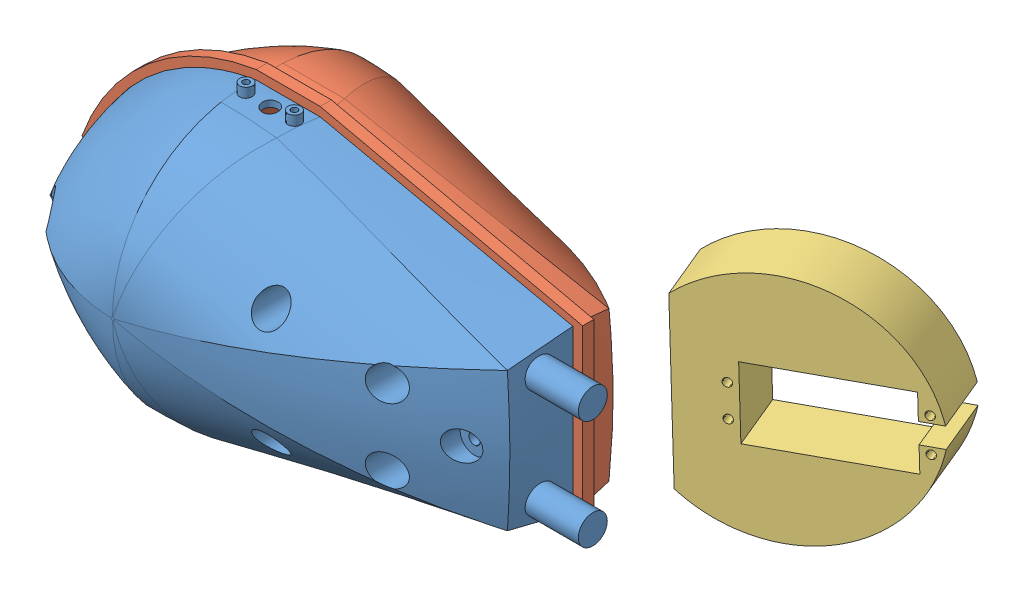
SolidWorks assembly Assem1, configuration Default. Lengths in mm.
Overall size (257.23 90 116.19).
3 component instances, 3 part files, 3 mates.
Components (placement in the parent):
- 下面-1: 下面 [預設] at origin size (169.53 90 49.49)
- 上面-1: 上面 [預設] at (0 0 -2.1312) x (1 0 0) z (0 0 -1) size (189.68 89.69 63.09)
- 後面-1: 後面 [預設] at (149.3311 2.5455 -38.8722) x (0.072413 -0.996617 0.038884) z (0.414182 0.065514 0.907833) size (68.85 64.47 20)
Mates (geometry in assembly coordinates):
- Concentric1: concentric: cylinder of 下面-1 through (11.1989 0 47.7) axis (0 0 -1) radius 5; cylinder of 上面-1 through (11.1989 0 17.8688) axis (0 0 -1) radius 2.8
- Concentric2: concentric: circle of 下面-1; cylinder of 上面-1 through (138.1989 0 17.8688) axis (0 0 -1) radius 2.8
- Parallel1: parallel: cylinder of 下面-1 through (89.65 -18 47.7) axis (0 0 -1) radius 5; cylinder of 上面-1 through (89.6545 -18 17.8688) axis (0 0 -1) radius 2.8
